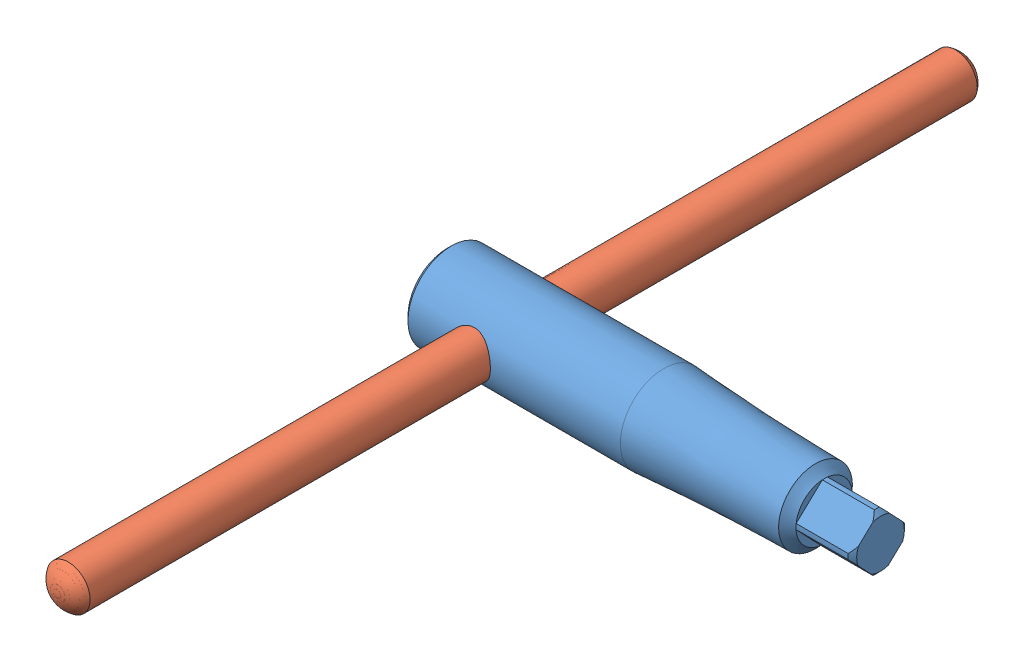
SolidWorks assembly chuckhandle, configuration ﾃﾞﾌｫﾙﾄ. Lengths in mm.
Overall size (100 21.13 210).
2 component instances, 2 part files, 7 mates.
Components (placement in the parent):
- chuckhandle-1: chuckhandle [ﾃﾞﾌｫﾙﾄ] at (-15 0 0) size (100 21.13 21.56)
- chuckhandle_handle-1: chuckhandle_handle [ﾃﾞﾌｫﾙﾄ] at (0 0 -105) x (0 0 1) z (-1 0 0) size (210 10 10)
Mates (geometry in assembly coordinates):
- Coincident2: coincident aligned: plane of chuckhandle-1 through (0 0 0) normal (1 0 0)
- Coincident3: coincident aligned: plane of chuckhandle-1 through (-15 0 0) normal (0 1 0)
- Parallel1: parallel anti-aligned: plane of chuckhandle-1 through (0 0 0) normal (1 0 0); plane of chuckhandle_handle-1 through (0 0 -105) normal (-1 0 0)
- Coincident4: coincident aligned: plane of chuckhandle_handle-1 through (0 0 -105) normal (0 1 0)
- Coincident5: coincident anti-aligned: plane of chuckhandle_handle-1 through (0 0 -105) normal (-1 0 0)
- Coincident6: coincident aligned: plane of chuckhandle-1 through (-15 0 0) normal (0 0 1)
- Coincident7: coincident aligned: plane of chuckhandle_handle-1 through (0 0 0) normal (0 0 1)
